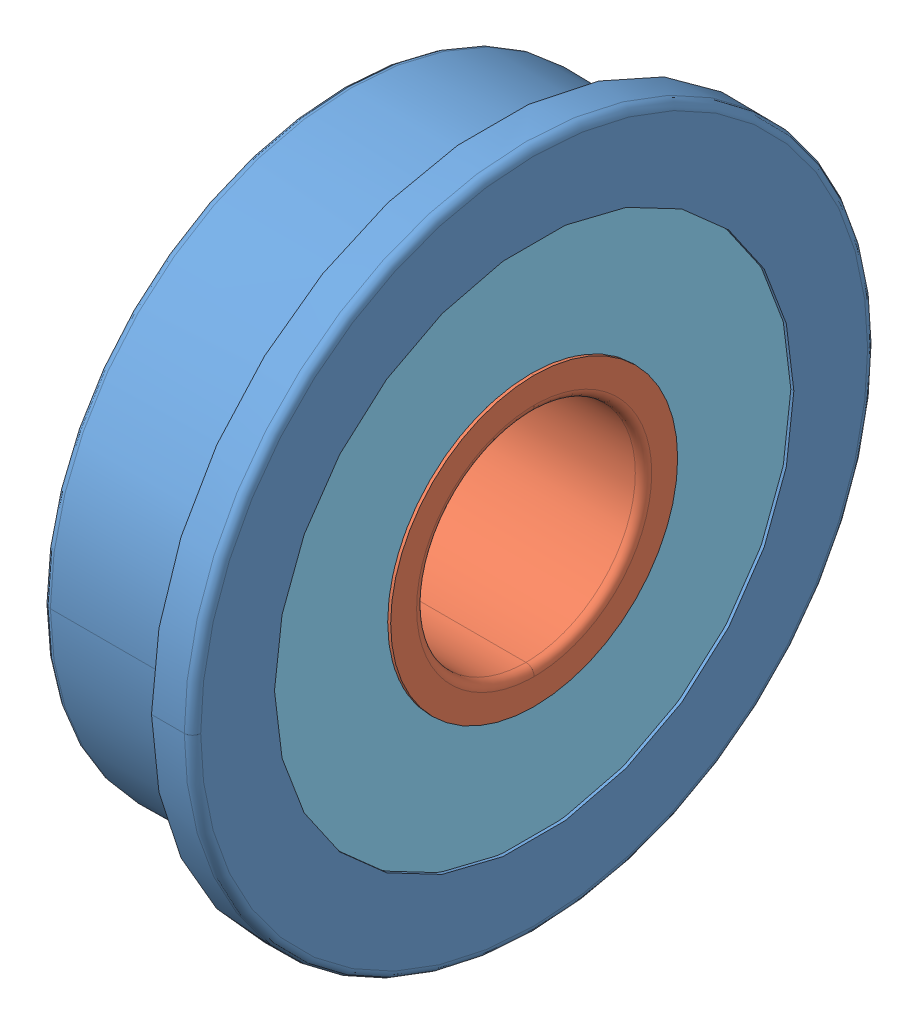
SolidWorks assembly F608ZZ, configuration Default. Lengths in mm.
Overall size (7 25 25).
12 component instances, 5 part files, 0 mates.
Components (placement in the parent):
- _F608ZZ_Outer_Ring_2-1: _F608ZZ_Outer_Ring_2 [Default] at origin size (7 25 25)
- _F608ZZ_Inner_Ring_4-1: _F608ZZ_Inner_Ring_4 [Default] x (1 0 0) z (0 -1 0) size (7 12.14 12.14)
- _F608ZZ_Shield1_6-1: _F608ZZ_Shield1_6 [Default] at (0.875 0 0) x (-1 0 0) z (0 -1 0) size (0.33 19 19)
- _F608ZZ_Ball_8-1: _F608ZZ_Ball_8 [Default] at (3.5 0 7.5) x (1 0 0) z (0 -1 0) size (4.2 4.2 4.2)
- _F608ZZ_Ball_8-2: _F608ZZ_Ball_8 [Default] at (3.5 -5.3033 5.3033) x (1 0 0) z (0 -1 0) size (4.2 4.2 4.2)
- _F608ZZ_Ball_8-3: _F608ZZ_Ball_8 [Default] at (3.5 -7.5 0) x (1 0 0) z (0 -1 0) size (4.2 4.2 4.2)
- _F608ZZ_Ball_8-4: _F608ZZ_Ball_8 [Default] at (3.5 -5.3033 -5.3033) x (1 0 0) z (0 -1 0) size (4.2 4.2 4.2)
- _F608ZZ_Ball_8-5: _F608ZZ_Ball_8 [Default] at (3.5 0 -7.5) x (1 0 0) z (0 -1 0) size (4.2 4.2 4.2)
- _F608ZZ_Ball_8-6: _F608ZZ_Ball_8 [Default] at (3.5 5.3033 -5.3033) x (1 0 0) z (0 -1 0) size (4.2 4.2 4.2)
- _F608ZZ_Ball_8-7: _F608ZZ_Ball_8 [Default] at (3.5 7.5 0) x (1 0 0) z (0 -1 0) size (4.2 4.2 4.2)
- _F608ZZ_Ball_8-8: _F608ZZ_Ball_8 [Default] at (3.5 5.3033 5.3033) x (1 0 0) z (0 -1 0) size (4.2 4.2 4.2)
- _F608ZZ_Shield2_17-1: _F608ZZ_Shield2_17 [Default] at origin size (0.33 19 19)
